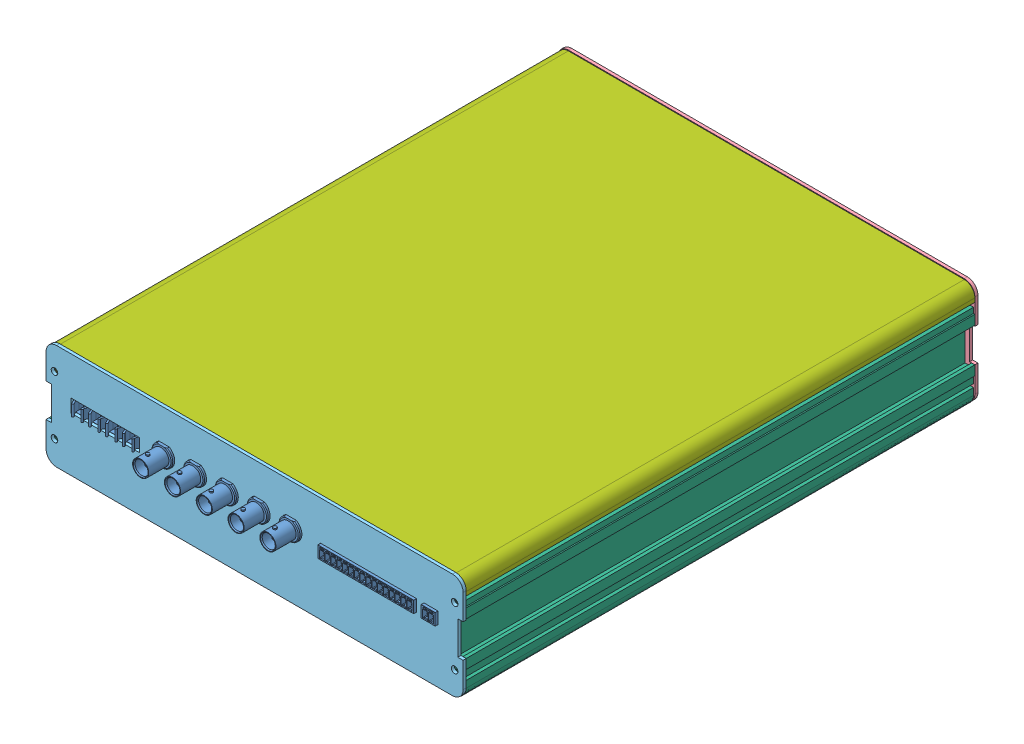
SolidWorks assembly PRiME_CSaAF, configuration Default. Lengths in mm.
Overall size (249.94 64.12 331.39).
11 component instances, 7 part files, 13 mates.
Components (placement in the parent):
- MW_PRiME_NI-USB7856R-Support-1: MW_PRiME_NI-USB7856R-Support [Default] at (0 0 -304.8) x (-1 0 0) z (0 0 -1) size (234.44 21 331.39)
  - PRiME_NI-USB7856R-Support-1: PRiME_NI-USB7856R-Support [Default] at (-234.442 -1.6 0) x (1 0 0) z (0 1 0) size (234.44 331.39 21)
- MW_PRiME_Launchpad-1: MW_PRiME_Launchpad [Default] at (4.572 12.1 -304.8) x (-1 0 0) z (0 0 -1) size (58.42 5.52 75.08)
  - PRiME_Launchpad-1: PRiME_Launchpad [Default] at (-3.81 -1.6 -73.66) x (-1 0 0) z (0 1 0) size (58.42 75.08 5.52)
- MW_PRiME_NI_USA_7856R_OEM-2: MW_PRiME_NI_USA_7856R_OEM [Default] at (65.2758 -11.548 -304.829) x (-1 0 0) z (0 0 -1) size (162.56 21.46 182.3)
  - PRiME_NI_USA_7856R_OEM-1: PRiME_NI_USA_7856R_OEM [Default] at (-81.28 -1.5748 -87.63) x (0 0 1) z (0 1 0) size (182.3 162.56 21.46)
- MW_PRiME_IA6161-1: MW_PRiME_IA6161 [Simplified] at (-7.747 -33.4643 -328.422) size (249.94 64.12 308.51)
  - PRiME_IA-6161_Panel-1: PRiME_IA-6161_Panel [Default] at (124.968 32.5438 23.622) x (-1 0 0) z (0 0 -1) size (249.94 63.14 1.85)
  - PRiME_IA-6161_BackPanel-1: PRiME_IA-6161_BackPanel [Default] at (124.968 32.5438 328.422) x (-1 0 0) z (0 0 1) size (249.94 63.14 1.85)
  - PRiME_IA-6161_MainBody-2: PRiME_IA-6161_MainBody [Default] at (124.968 52.07 328.422) x (-1 0 0) z (0 0 -1) size (249.94 52.07 304.8)
  - PRiME_IA-6161_Lid-1: PRiME_IA-6161_Lid [Default] at (124.968 63.6595 328.422) x (-1 0 0) z (0 0 -1) size (249.94 15.75 304.8)
Mates (geometry in assembly coordinates):
- Coincident36: coincident anti-aligned: plane of MW_PRiME_NI-USB7856R-Support-1 through (117.221 0 -304.8) normal (1 0 0); plane of MW_PRiME_IA6161-1 through (117.221 -33.4643 -328.422) normal (-1 0 0)
- Coincident26: coincident aligned: plane of MW_PRiME_NI-USB7856R-Support-1 through (0 0 0) normal (0 0 1); plane of assembly through (0 0 0) normal (0 0 1)
- Coincident27: coincident aligned: plane of MW_PRiME_NI-USB7856R-Support-1; plane of assembly through (0 0 0) normal (0 1 0)
- Coincident28: coincident anti-aligned: plane of MW_PRiME_NI-USB7856R-Support-1 through (0 0 -304.8) normal (-1 0 0); plane of assembly through (0 0 0) normal (1 0 0)
- Parallel3: parallel aligned: plane of MW_PRiME_NI-USB7856R-Support-1 through (0 0 -304.8) normal (0 0 -1); plane of MW_PRiME_Launchpad-1 through (4.572 12.1 -304.8) normal (0 0 -1)
- Distance1: distance = 8 mm anti-aligned: plane of MW_PRiME_Launchpad-1; plane of MW_PRiME_NI-USB7856R-Support-1
- Coincident35: coincident aligned: line of MW_PRiME_NI-USB7856R-Support-1 through (10.922 -1.6 -266.7) axis (0 1 0); line of MW_PRiME_Launchpad-1 through (10.922 10.5 -266.7) axis (0 1 0)
- Coincident37: coincident anti-aligned: plane of MW_PRiME_NI-USB7856R-Support-1 through (117.221 0 -304.8) normal (1 0 0); plane of MW_PRiME_IA6161-1 through (117.221 -33.4643 -328.422) normal (-1 0 0)
- Coincident38: coincident aligned: plane of MW_PRiME_NI-USB7856R-Support-1 through (0 0 -152.4) normal (0 0 1); plane of MW_PRiME_IA6161-1 through (-7.747 -33.4643 -152.4) normal (0 0 1)
- Coincident39: coincident anti-aligned: plane of MW_PRiME_NI-USB7856R-Support-1; plane of MW_PRiME_IA6161-1/PRiME_IA-6161_MainBody-2
- Coincident42: coincident anti-aligned: line of MW_PRiME_NI-USB7856R-Support-1 through (131.392 -1.6 -141.38) axis (0 1 0); line of MW_PRiME_NI_USA_7856R_OEM-2 through (131.392 -11.548 -141.38) axis (0 -1 0)
- Coincident43: coincident anti-aligned: plane of MW_PRiME_NI-USB7856R-Support-1; plane of MW_PRiME_NI_USA_7856R_OEM-2
- Parallel5: parallel aligned: plane of MW_PRiME_NI-USB7856R-Support-1 through (0 0 -304.8) normal (0 0 -1); plane of MW_PRiME_NI_USA_7856R_OEM-2 through (65.2758 -11.548 -304.829) normal (0 0 -1)
